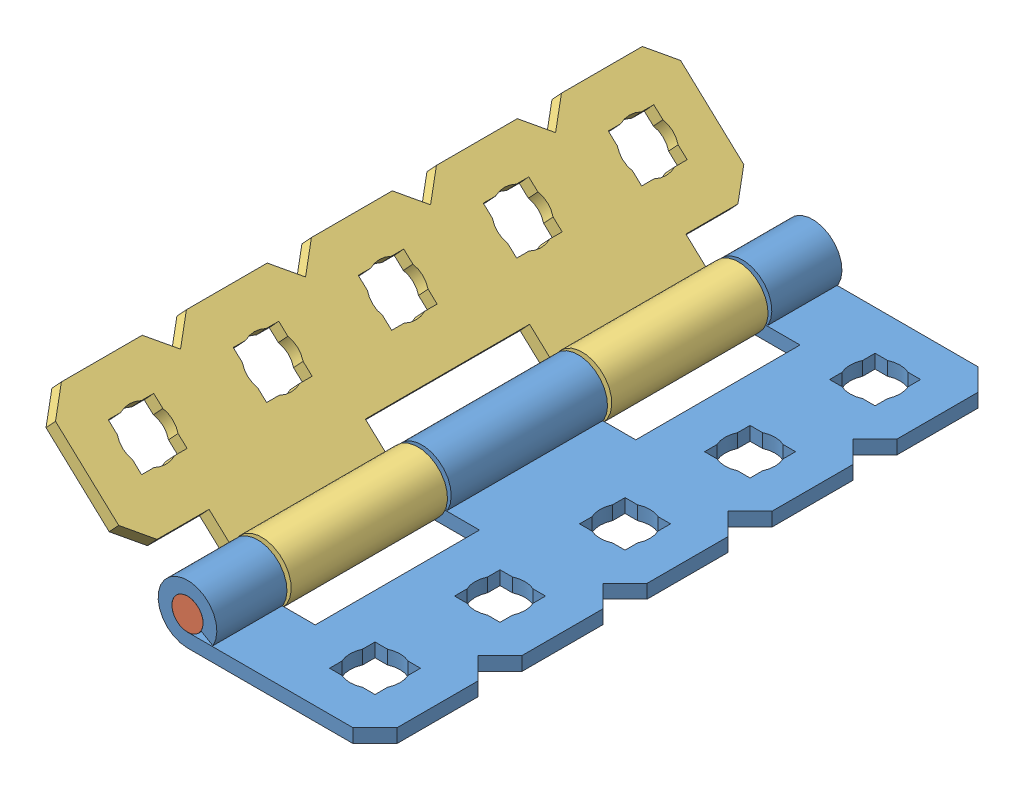
SolidWorks assembly Hinge, configuration Default. Lengths in mm.
Overall size (35.07 19.41 63.5).
3 component instances, 3 part files, 4 mates.
Components (placement in the parent):
- Copy of VEX-HINGE-1 RevA^Hinge-1: Copy of VEX-HINGE-1 RevA^Hinge [Default] at (58.0649 32.8359 32.9251) size (22.03 5.97 63.5) (virtual)
- Copy of VEX-HINGE-PIN^Hinge-1: Copy of VEX-HINGE-PIN^Hinge [Default] at (42.1899 35.8204 1.1751) size (3.17 3.17 63.5) (virtual)
- Copy of VEX-HINGE-2 RevA^Hinge-1: Copy of VEX-HINGE-2 RevA^Hinge [Default] at (28.4985 44.4006 32.9251) x (-0.733604 0.679578 0) z (0 0 -1) size (22.06 6.02 63.5) (virtual)
Mates (geometry in assembly coordinates):
- Width1: width anti-aligned: plane of Copy of VEX-HINGE-1 RevA^Hinge-1 through (42.1899 34.2329 64.6751) normal (0 0 1); plane of VEX-HINGE-PIN-1 through (42.1899 34.2329 1.1751) normal (0 0 -1); plane of Copy of VEX-HINGE-1 RevA^Hinge-1 through (42.1899 35.8204 1.1751) normal (0 0 -1); plane of VEX-HINGE-PIN-1 through (42.1899 35.8204 64.6751) normal (0 0 1)
- Concentric1: concentric anti-aligned: cylinder of Copy of VEX-HINGE-1 RevA^Hinge-1 through (42.1899 35.8204 13.6826) axis (0 0 1) radius 1.5875; cylinder of VEX-HINGE-PIN-1 through (42.1899 35.8204 64.6751) axis (0 0 -1) radius 1.5875
- Width2: width anti-aligned: plane of Copy of VEX-HINGE-1 RevA^Hinge-1 through (42.1899 34.2329 64.6751) normal (0 0 1); plane of Copy of VEX-HINGE-2 RevA^Hinge-1 through (42.1899 34.2329 1.1751) normal (0 0 -1); plane of Copy of VEX-HINGE-1 RevA^Hinge-1 through (49.0556 27.2963 8.7062) normal (0 0 -1); plane of Copy of VEX-HINGE-2 RevA^Hinge-1 through (49.0556 27.2963 57.144) normal (0 0 1)
- Concentric2: concentric aligned: cylinder of Copy of VEX-HINGE-PIN^Hinge-1 through (42.1899 35.8204 64.6751) axis (0 0 -1) radius 1.5875; cylinder of VEX-HINGE-2 RevA-1 through (42.1899 35.8204 35.9132) axis (0 0 -1) radius 1.5875
